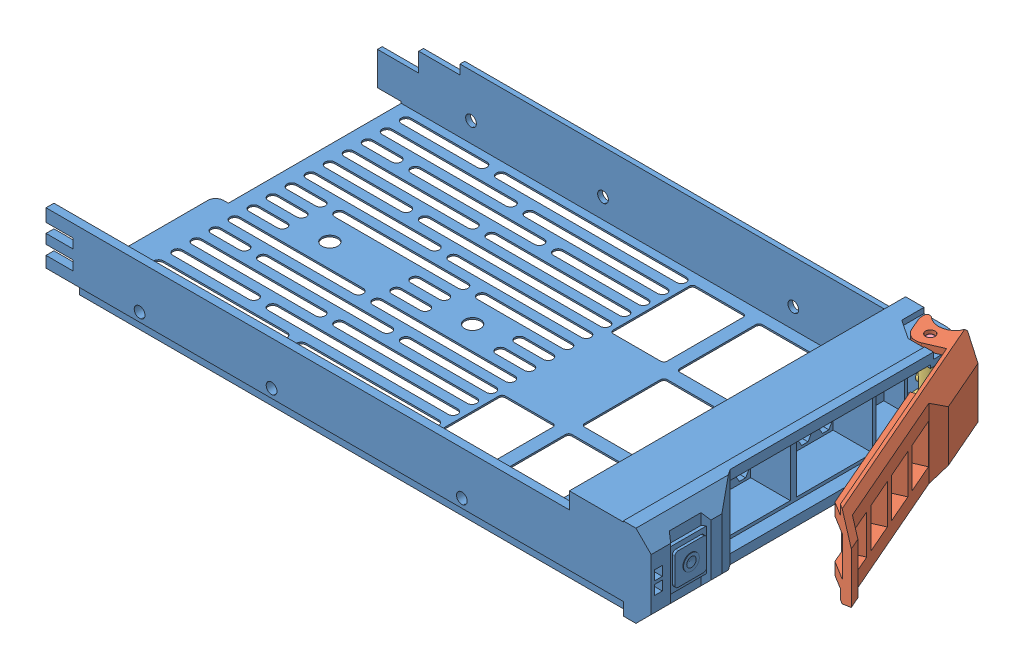
SolidWorks assembly 硬盘托架装配体, configuration 默认. Lengths in mm.
Overall size (220.6 26 110.23).
4 component instances, 4 part files, 7 mates.
Components (placement in the parent):
- 硬盘托架-1: 硬盘托架 [默认] at (-103.8436 -9.5073 191) size (191 26 106)
- 硬盘托架把手-3: 硬盘托架把手 [默认] at (108.4968 -9.5073 214.2918) x (0.917212 0 -0.3984) z (0 -1 0) size (16 83.88 26)
- 硬盘托架轴-1: 硬盘托架轴 [默认] at (75.4564 -5.5073 144.5) size (9 17.5 9)
- 硬盘托架插销-2: 硬盘托架插销 [默认] at (75.4564 -9.3073 144.5) size (2.8 25 2.8)
Mates (geometry in assembly coordinates):
- 距离1: distance = 0.5 mm aligned: plane of 硬盘托架插销-2 through (75.4564 15.6927 144.5) normal (0 1 0); plane of 硬盘托架-1 through (-103.8436 16.1927 191) normal (0 1 0)
- 重合22: coincident anti-aligned: plane of 硬盘托架-1 through (73.9564 14.4927 145) normal (0 1 0); plane of 硬盘托架把手-3 through (74.7676 14.4927 135.722) normal (0 -1 0)
- 重合23: coincident anti-aligned: axis of 硬盘托架-1 through (75.4564 -5.5073 144.5) axis (0 -1 0); axis of 硬盘托架轴-1 through (75.4564 -5.5073 144.5) axis (0 1 0)
- 重合24: coincident aligned: axis of 硬盘托架-1 through (68.4564 3.4927 144.5) axis (-1 0 0); axis of 硬盘托架轴-1 through (74.2064 3.4927 144.5) axis (-1 0 0)
- 重合25: coincident anti-aligned: axis of 硬盘托架-1 through (75.4564 -5.5073 144.5) axis (0 -1 0); axis of 硬盘托架插销-2 through (75.4564 -8.8073 144.5) axis (0 1 0)
- 重合27: coincident aligned: axis of 硬盘托架-1 through (75.4564 -5.5073 144.5) axis (0 -1 0); axis of 硬盘托架把手-3 through (75.4564 -7.5073 144.5) axis (0 -1 0)
- LimitAngle1: limit planar angle = 0.409772 rad anti-aligned: plane of 硬盘托架把手-3 through (94.914 3.4927 175.4909) normal (-0.917212 0 0.3984); plane of 硬盘托架-1 through (80.9564 -9.5073 138) normal (1 0 0)
